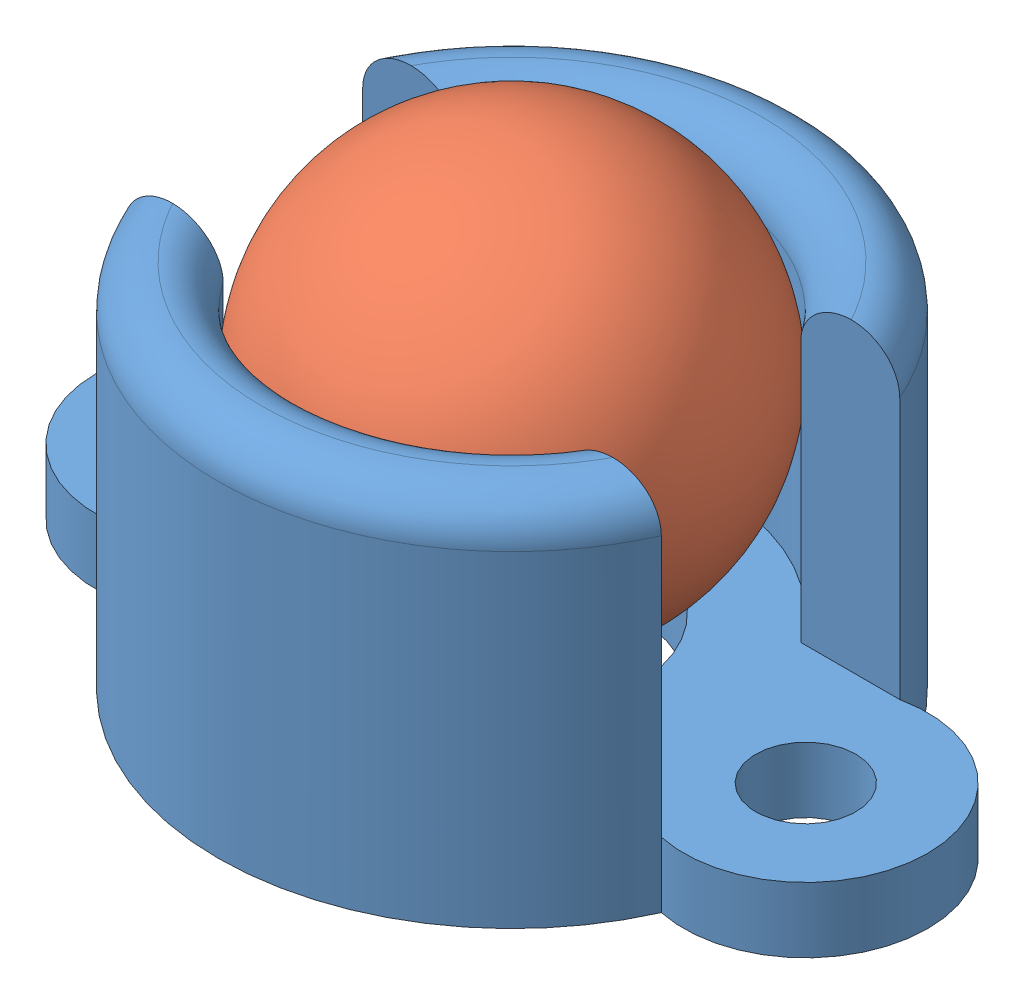
SolidWorks assembly comBallCaster, configuration Default. Lengths in mm.
Overall size (19.1 14.63 15.62).
2 component instances, 2 part files, 2 mates.
Components (placement in the parent):
- ballcaster-1: ballcaster [Default] at (8.2473 5.6001 14.117) size (19.1 8.6 13.5)
- Ball-1: Ball [Default] at (8.2473 11.8626 14.117) x (-0.239174 -0.54017 -0.806853) z (-0.907177 -0.171932 0.384017) size (9.53 9.53 9.53)
Mates (geometry in assembly coordinates):
- Tangent1: tangent anti-aligned: plane of ballcaster-1 through (11.6223 7.1001 14.117) normal (0 1 0); sphere of Ball-1
- Tangent5: tangent aligned: cylinder of ballcaster-1 through (8.2473 14.1001 14.117) axis (0 -1 0) radius 4.7625; sphere of Ball-1
